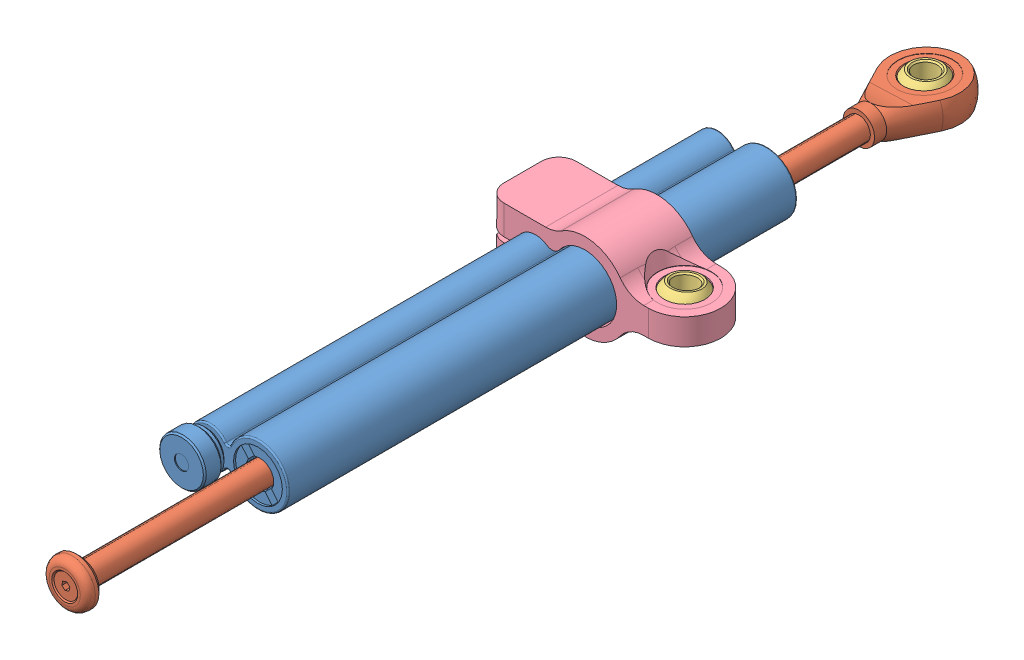
SolidWorks assembly Ohlins steering damper 90mm stroke, configuration Default. Lengths in mm.
Overall size (68.5 30 310.45).
5 component instances, 4 part files, 6 mates.
Components (placement in the parent):
- Ohlins damper body-1: Ohlins damper body [Default] at origin size (35.5 20.9 185.4)
- Ohlins damper rod-1: Ohlins damper rod [Default] at (0 0 -142.7052) x (0.99916 0.040991 0) z (0 0 1) size (25.9 16 310.45)
- Ohlins damper ball end-1: Ohlins damper ball end [Default] at (0 0 -142.7052) x (-0.004964 0.999633 -0.026631) z (-0.149418 0.025591 0.988443) size (12 15.9 15.9)
- Damper bracket-1: Damper bracket [Default] at (0 0 -37.5) x (-1 0 0) z (0 0 1) size (68.5 30 25)
- Ohlins damper ball end-2: Ohlins damper ball end [Default] at (22 0 -37.5) x (-0.025609 0.995875 -0.087046) z (0.044614 0.088127 0.99511) size (12 15.9 15.9)
Mates (geometry in assembly coordinates):
- Concentric1: concentric: sphere of Ohlins damper rod-1; sphere of Ohlins damper ball end-1
- Concentric2: concentric aligned: cylinder of Ohlins damper body-1 through (0 0 88) axis (0 0 -1) radius 10.45; cylinder of Ohlins damper rod-1 through (0 0 -142.7052) axis (0 0 -1) radius 4
- Concentric3: concentric: sphere of Damper bracket-1; sphere of Ohlins damper ball end-2
- Concentric4: concentric aligned: cylinder of Ohlins damper body-1 through (-17 0 88) axis (0 0 -1) radius 6.95; cylinder of Damper bracket-1 through (-17 0 -25) axis (0 0 -1) radius 7
- Concentric5: concentric aligned: cylinder of Ohlins damper body-1 through (0 0 88) axis (0 0 -1) radius 10.45; cylinder of Damper bracket-1 through (0 0 -25) axis (0 0 -1) radius 11
- Distance1: distance = 38 mm aligned: plane of Damper bracket-1 through (-17 0 -50) normal (0 0 -1); plane of Ohlins damper body-1 through (-8.5 0 -88) normal (0 0 -1)
